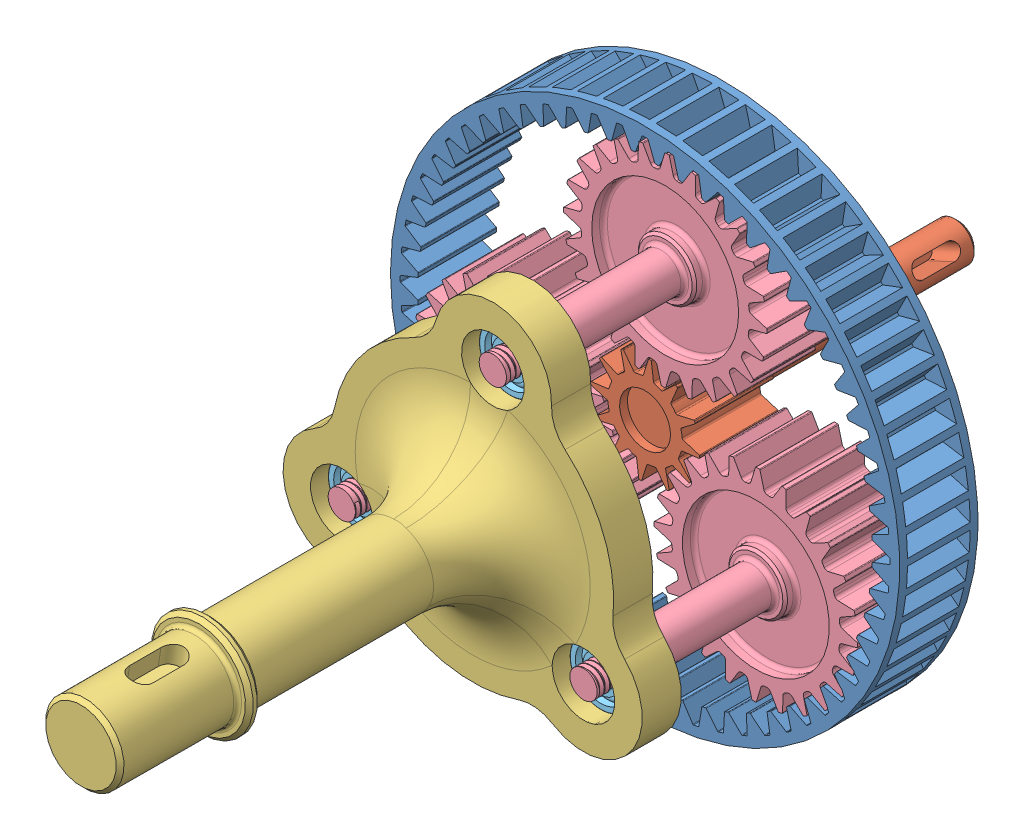
SolidWorks assembly Planetary Gearbox, configuration Default. Lengths in mm.
Overall size (66.88 65 112).
9 component instances, 5 part files, 11 mates.
Components (placement in the parent):
- Ring Gear-1: Ring Gear [Default] at (9.6546 32.0421 53.8778) size (65 65 10)
- Sun Gear-1: Sun Gear [Default] at (9.6546 32.0421 63.8778) x (0 0 -1) z (0.420623 -0.907235 0) size (40 14 14)
- Drive Shaft-1: Drive Shaft [Default] at (9.6546 32.0421 80.8768) x (0 0 1) z (-0.989761 0.142733 0) size (55 43.5 46.18)
- Planetary Gear-1: Planetary Gear [Default] at (12.2238 49.8578 53.8778) x (0 0 1) z (-0.017956 -0.999839 0) size (32.1 26 26)
- instrument ball bearing_ai-2: instrument ball bearing_ai [AFBMA 12.2 - 0.1250 - 0.3125 - 0.1094 - 10,SI,NC,10] at (12.2238 49.8578 82.2662) x (0 0 1) z (-1 0 0) size (2.78 7.94 7.94)
- instrument ball bearing_ai-3: instrument ball bearing_ai [AFBMA 12.2 - 0.1250 - 0.3125 - 0.1094 - 10,SI,NC,10] at (-7.0588 25.3593 82.2662) x (0 0 1) z (0.5 -0.866025 0) size (2.78 7.94 7.94)
- instrument ball bearing_ai-4: instrument ball bearing_ai [AFBMA 12.2 - 0.1250 - 0.3125 - 0.1094 - 10,SI,NC,10] at (23.7989 20.9093 82.2662) x (0 0 1) z (0.5 0.866025 0) size (2.78 7.94 7.94)
- Planetary Gear-2: Planetary Gear [Default] at (-7.0588 25.3593 53.8778) x (0 0 1) z (0.874864 0.484369 0) size (32.1 26 26)
- Planetary Gear-3: Planetary Gear [Default] at (23.7989 20.9093 53.8778) x (0 0 1) z (-0.856908 0.515469 0) size (32.1 26 26)
Mates (geometry in assembly coordinates):
- Concentric1: concentric: cylinder of Ring Gear-1 through (9.6546 32.0421 63.8778) axis (0 0 -1) radius 32.5; cylinder of Sun Gear-1 through (9.6546 32.0421 23.8778) axis (0 0 1) radius 2.5
- Coincident1: coincident: plane of Ring Gear-1 through (9.6546 32.0421 63.8778) normal (0 0 1); plane of Sun Gear-1 through (13.6767 26.4356 63.8778) normal (0 0 1)
- Concentric3: concentric: cylinder of Sun Gear-1 through (9.6546 32.0421 23.8778) axis (0 0 1) radius 2.5; cylinder of Drive Shaft-1 through (9.6546 32.0421 135.8768) axis (0 0 -1) radius 5
- Concentric4: concentric: cylinder of Drive Shaft-1 through (25.7243 23.9327 85.8768) axis (0 0 -1) radius 4; cylinder of Planetary Gear-1 through (25.7243 23.9327 85.8778) axis (0 0 -1) radius 2.5
- Concentric5: concentric: cylinder of Drive Shaft-1 through (25.7243 23.9327 85.8768) axis (0 0 -1) radius 4; cylinder of instrument ball bearing_ai-2 through (25.7243 23.9327 61.6287) axis (0 0 1) radius 3.9688
- Coincident3: coincident: plane of Planetary Gear-1 through (25.7243 23.9327 80.8768) normal (0 0 1); plane of instrument ball bearing_ai-2 through (25.7243 26.2345 80.8768) normal (0 0 -1)
- Coincident4: coincident: plane of Ring Gear-1 through (9.6546 32.0421 53.8778) normal (0 0 -1); plane of Planetary Gear-1 through (33.9352 33.8821 53.8778) normal (0 0 -1)
- Coincident5: coincident: plane of Drive Shaft-1 through (21.0932 33.2293 80.8768) normal (0 0 -1); plane of instrument ball bearing_ai-2 through (25.7243 27.187 80.8768) normal (0 0 -1)
- GearMate1: gear = 7.5 : 5 mm: cylinder of Sun Gear-1 through (9.6546 32.0421 23.8778) axis (0 0 1) radius 2.5; cylinder of Planetary Gear-2 through (8.6428 50.0137 55.3778) axis (0 0 -1) radius 3.75
- GearMate2: gear = 65 : 7.5 mm: cylinder of Planetary Gear-2 through (8.6428 50.0137 55.3778) axis (0 0 -1) radius 3.75; cylinder of Ring Gear-1 through (9.6546 32.0421 63.8778) axis (0 0 -1) radius 32.5
- GearMate3: gear = 65 : 7.5 mm: cylinder of Planetary Gear-3 through (-5.4033 22.1801 55.3778) axis (0 0 -1) radius 3.75; cylinder of Ring Gear-1 through (9.6546 32.0421 63.8778) axis (0 0 -1) radius 32.5
